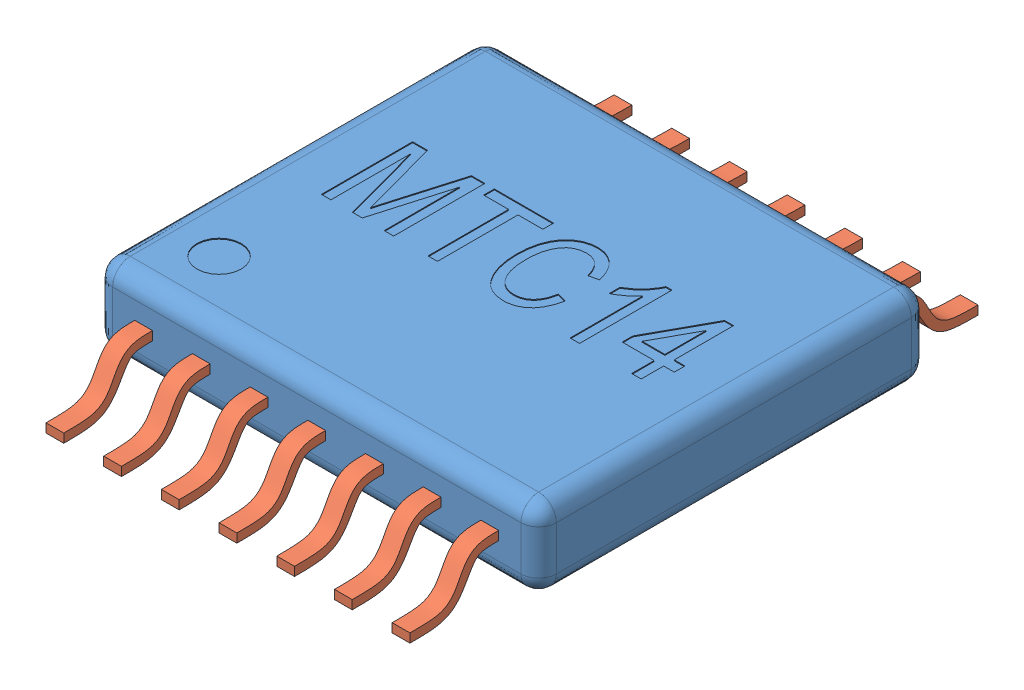
SolidWorks assembly MTC14, configuration Default. Lengths in mm.
Overall size (5 1 6.4).
15 component instances, 2 part files, 7 mates.
Components (placement in the parent):
- Body-1: Body [Default] at (0 0.55 0) size (5 0.9 4.4)
- Pin-1: Pin [Default] at (-1.95 0.05 3.2) x (0 0 -1) z (0 -1 0) size (1 0.2 0.6)
- Pin-2: Pin [Default] at (-1.3 0.05 3.2) x (0 0 -1) z (0 -1 0) size (1 0.2 0.6)
- Pin-3: Pin [Default] at (-0.65 0.05 3.2) x (0 0 -1) z (0 -1 0) size (1 0.2 0.6)
- Pin-4: Pin [Default] at (0 0.05 3.2) x (0 0 -1) z (0 -1 0) size (1 0.2 0.6)
- Pin-5: Pin [Default] at (0.65 0.05 3.2) x (0 0 -1) z (0 -1 0) size (1 0.2 0.6)
- Pin-6: Pin [Default] at (1.3 0.05 3.2) x (0 0 -1) z (0 -1 0) size (1 0.2 0.6)
- Pin-7: Pin [Default] at (1.95 0.05 3.2) x (0 0 -1) z (0 -1 0) size (1 0.2 0.6)
- Pin-8: Pin [Default] at (-1.95 0.05 -3.2) x (0 0 1) z (0 -1 0) size (1 0.2 0.6)
- Pin-9: Pin [Default] at (-1.3 0.05 -3.2) x (0 0 1) z (0 -1 0) size (1 0.2 0.6)
- Pin-10: Pin [Default] at (-0.65 0.05 -3.2) x (0 0 1) z (0 -1 0) size (1 0.2 0.6)
- Pin-11: Pin [Default] at (0 0.05 -3.2) x (0 0 1) z (0 -1 0) size (1 0.2 0.6)
- Pin-12: Pin [Default] at (0.65 0.05 -3.2) x (0 0 1) z (0 -1 0) size (1 0.2 0.6)
- Pin-13: Pin [Default] at (1.3 0.05 -3.2) x (0 0 1) z (0 -1 0) size (1 0.2 0.6)
- Pin-14: Pin [Default] at (1.95 0.05 -3.2) x (0 0 1) z (0 -1 0) size (1 0.2 0.6)
Mates (geometry in assembly coordinates):
- Coincident1: coincident: plane of Body-1 through (0 0.35 0) normal (1 0 0); plane of assembly through (0 0 0) normal (1 0 0)
- Coincident2: coincident: plane of Body-1 through (0 0.35 0) normal (0 0 1); plane of assembly through (0 0 0) normal (0 0 1)
- Distance1: distance = 0.1 mm: plane of Body-1 through (0 0.1 0) normal (0 -1 0); plane of assembly through (0 0 0) normal (0 1 0)
- Coincident4: coincident: plane of Body-1 through (-2.5 0.8 2.2) normal (0 0 1); plane of Pin-1 through (-1.85 0.3 2.2) normal (0 0 -1)
- Parallel1: parallel: plane of Body-1 through (0 0.35 0) normal (1 0 0); plane of Pin-1 through (-1.95 -0.15 3.2) normal (1 0 0)
- Distance2: distance = 1.95 mm: plane of Pin-1 through (-1.95 0.05 3.2) normal (1 0 0); plane of Body-1 through (0 0.55 0) normal (1 0 0)
- Coincident7: coincident: plane of Body-1 through (0 0.35 0) normal (0 1 0); plane of Pin-1 through (-1.95 0.35 3.2) normal (0 -1 0)
